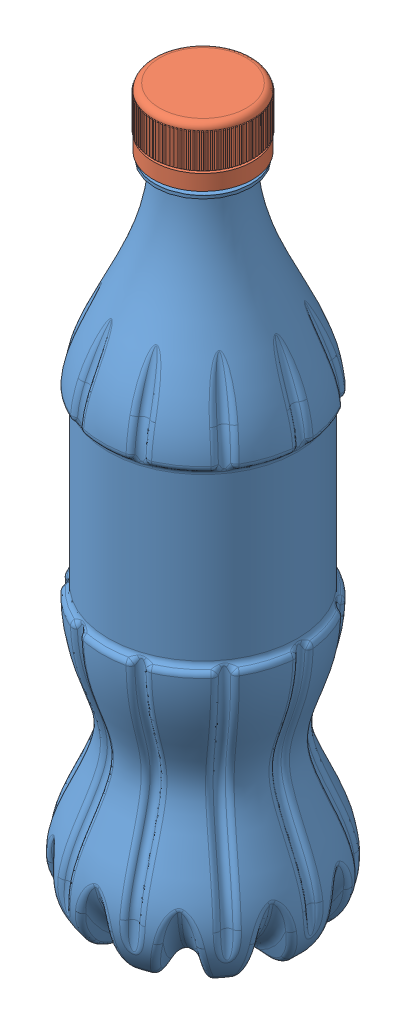
SolidWorks assembly Practice Model - Coke Bottle, configuration Default. Lengths in mm.
Overall size (87.34 232.17 87.34).
3 component instances, 3 part files, 6 mates.
Components (placement in the parent):
- Practice Model- Coca Cola Bottle-1: Practice Model- Coca Cola Bottle [Default] at (2.7447 -127.6308 7.3396) size (87.34 230.72 87.34)
- Practice Model - Bottle Cap-1: Practice Model - Bottle Cap [Default] at (2.7447 84.8692 7.3396) x (0.824376 0 0.566043) z (-0.566043 0 0.824376) size (32.5 19 32.5)
- Coke-1: Coke [Default] x (1 0 0) z (0 1 0) size (73.32 71.88 158.03)
Mates (geometry in assembly coordinates):
- Concentric1: concentric aligned: circle of Practice Model- Coca Cola Bottle-1; circle of Practice Model - Bottle Cap-1
- Distance2: distance = 0.5 mm anti-aligned: plane of Practice Model - Bottle Cap-1 through (10.9523 87.8692 -4.6138) normal (0 1 0); plane of Practice Model- Coca Cola Bottle-1 through (16.7447 88.3692 7.3396) normal (0 -1 0)
- InPlace3: in place: plane of Coke-1 through (0 0 0) normal (0 1 0); moOrthogonalPlaneRef_w of Coke-1 through (0 0 0) normal (0 0 -1); plane of Coke-1 through (0 0 0) normal (1 0 0); unknown of Coke-1
- Coincident9: coincident aligned: 
- Coincident10: coincident aligned: plane of Coke^Practice Model - Coke Bottle-1 through (0 0 0) normal (0 0 -1)
- Coincident11: coincident anti-aligned: plane of Coke^Practice Model - Coke Bottle-1 through (0 0 0) normal (1 0 0)
